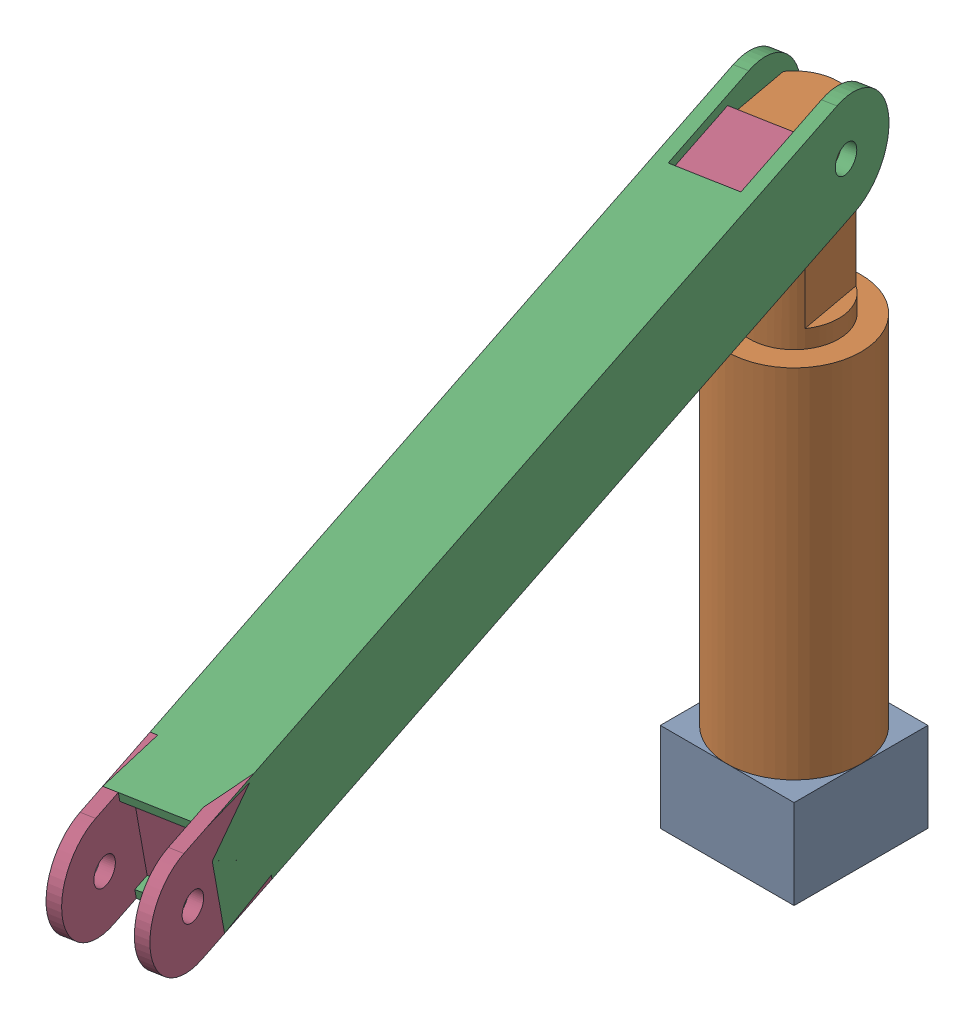
SolidWorks assembly OOP, configuration Domyślna. Lengths in mm.
Overall size (31.4 74.12 106.31).
4 component instances, 4 part files, 6 mates.
Components (placement in the parent):
- Podstawa-1: Podstawa [Domyślna] at origin size (15 20 15)
- Podstawa-P-1: Podstawa-P [Domyślna] at (0 10 0) x (0.18056 0 0.983564) z (-0.983564 0 0.18056) size (15 60 15)
- P-R-1: P-R [Domyślna] at (4.9178 67 -0.9028) x (0.176563 -0.209239 0.961792) z (-0.03778 -0.977864 -0.2058) size (96 10 12)
- R-Q-1: R-Q [Domyślna] at (21.38 47.4913 88.7713) x (-0.176563 0.209239 -0.961792) z (0.03778 0.977864 0.2058) size (96 10 12)
Mates (geometry in assembly coordinates):
- Koncentryczne1: concentric aligned: cylinder of Podstawa-1 through (0 20 0) axis (0 -1 0) radius 5; cylinder of Podstawa-P-1 through (0 50 0) axis (0 -1 0) radius 5
- Wspólnie1: coincident anti-aligned: plane of Podstawa-1 through (0 10 0) normal (0 1 0); plane of Podstawa-P-1 through (0 10 0) normal (0 -1 0)
- Koncentryczne2: concentric anti-aligned: cylinder of Podstawa-P-1 through (6.3932 67 -1.1736) axis (-0.983564 0 0.18056) radius 1.5; cylinder of P-R-1 through (-4.9178 67 0.9028) axis (0.983564 0 -0.18056) radius 1.5
- Szerokość1: width anti-aligned: plane of P-R-1; plane of Podstawa-P-1; plane of P-R-1; plane of Podstawa-P-1
- Wspólnie3: coincident anti-aligned: plane of P-R-1 through (6.7716 68.7507 14.7336) normal (-0.03778 -0.977864 -0.2058); plane of R-Q-1 through (10.9511 54.473 81.8074) normal (0.03778 0.977864 0.2058)
- Wspólnie4: coincident anti-aligned: plane of P-R-1 through (-1.0969 68.7507 16.1781) normal (0.983564 0 -0.18056); plane of R-Q-1 through (10.5733 44.6944 79.7494) normal (-0.983564 0 0.18056)
